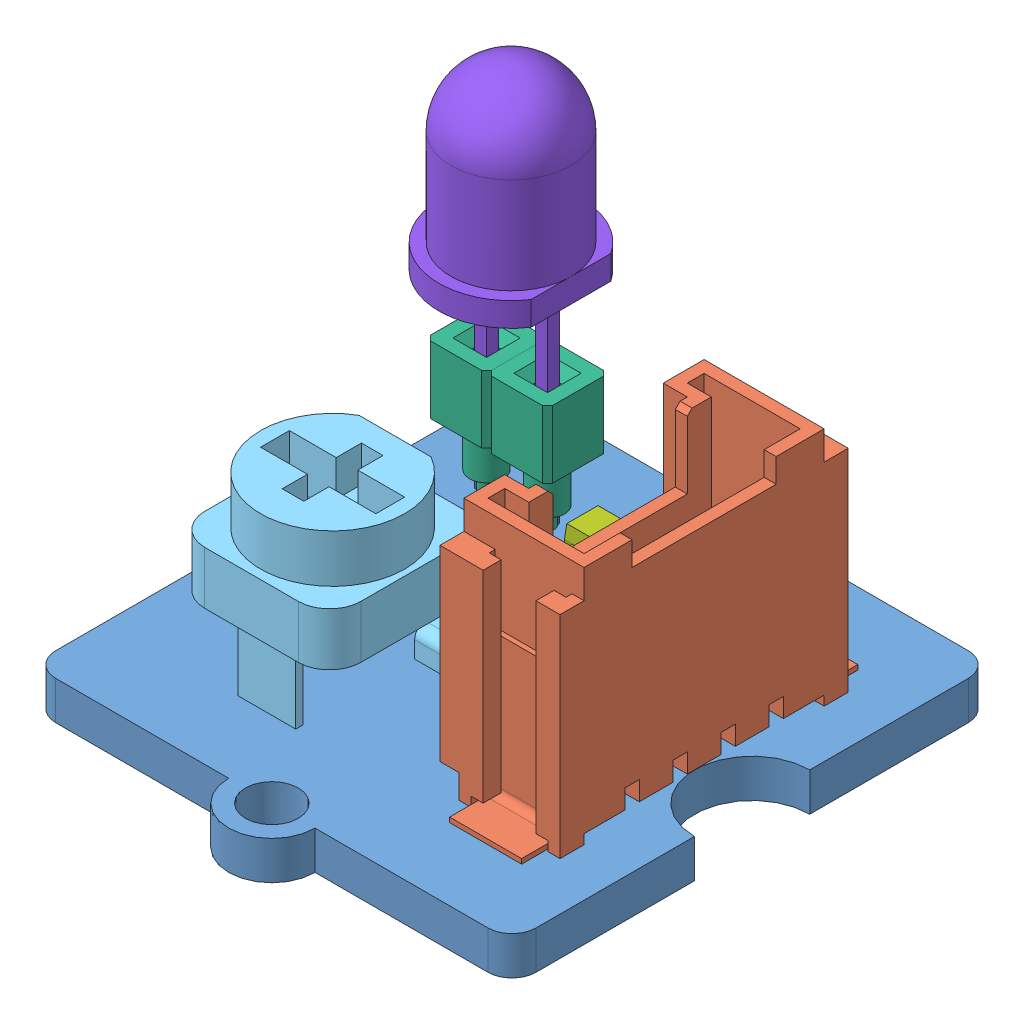
SolidWorks assembly Grove LED Rouge, configuration Défaut. Lengths in mm.
Overall size (20 19.1 23.6).
11 component instances, 8 part files, 16 mates.
Components (placement in the parent):
- PCB grove 20x20-1: PCB grove 20x20 [Défaut] at (7.4555 -4.1841 0) size (20 1.6 23.6)
- Connecteur Grove (droit CMS)-1: Connecteur Grove (droit CMS) [Défaut] at (10.4555 -2.5841 0) x (-1 0 0) z (0 1 0) size (6.5 14 10)
- 603 resistor 102-2: 603 resistor 102 [Default] at (3.6365 -2.5841 -1.49) size (2.36 0.62 1.03)
- 603 cap on pad-1: 603 cap on pad [Défaut] at (8.4655 -2.5841 -6.62) x (0 0 1) z (-1 0 0) size (2.76 0.91 1.12)
- 603 resistor 102-3: 603 resistor 102 [Default] at (6.6365 -2.5841 -1.49) size (2.36 0.62 1.03)
- 603 resistor 102-4: 603 resistor 102 [Default] at (6.6365 -2.5841 -2.99) size (2.36 0.62 1.03)
- Pot - RES_VAR1-1: Pot - RES_VAR1 [Défaut] at (4.0824 2.7159 4.0972) size (6.5 10.5 7.06)
- Contact F-1: Contact F [Défaut] at (0.621 0.0871 -5.7728) size (2.54 7.5 2.54)
- ssot3-1: ssot3 [Default] at (6.0932 -2.5841 -5.7439) size (3 1.13 3.09)
- LED 5mm Rouge-3: LED 5mm Rouge [Default] at (1.591 5.8159 -5.8228) x (1 0 0) z (0 1 0) size (5.5 6 17.5)
- Contact F-2: Contact F [Défaut] at (3.161 0.0871 -5.7728) size (2.54 7.5 2.54)
Mates (geometry in assembly coordinates):
- Distance1: distance = 2 mm aligned: plane of PCB grove 20x20-1 through (17.4555 -2.5841 0) normal (1 0 0); plane of Connecteur Grove (droit CMS)-1 through (15.4555 7.4159 6) normal (1 0 0)
- Distance2: distance = 4 mm aligned: plane of Connecteur Grove (droit CMS)-1 through (14.4555 7.4159 -6) normal (0 0 -1); plane of PCB grove 20x20-1 through (7.4555 -2.5841 -10) normal (0 0 -1)
- Coïncidente16: coincident anti-aligned: plane of PCB grove 20x20-1 through (7.4555 -2.5841 0) normal (0 1 0); plane of 603 resistor 102-2 through (3.6365 -2.5841 -1.49) normal (0 -1 0)
- Distance12: distance = 8 mm: plane of PCB grove 20x20-1 through (7.4555 -2.5841 -10) normal (0 0 -1); line of 603 resistor 102-2 through (4.8175 -2.5841 -2) axis (-1 0 0)
- Distance13: distance = 5 mm: line of 603 resistor 102-2 through (2.4555 -2.5841 -2) axis (0 0 1); plane of PCB grove 20x20-1 through (-2.5445 -2.5841 0) normal (-1 0 0)
- Coïncidente24: coincident anti-aligned: plane of PCB grove 20x20-1 through (7.4555 -2.5841 0) normal (0 1 0); plane of 603 cap on pad-1 through (8.4655 -2.5841 -6.62) normal (0 -1 0)
- Distance17: distance = 10.5 mm: line of PCB grove 20x20-1 through (-2.5445 -2.5841 9) axis (0 0 -1); line of 603 cap on pad-1 through (7.9555 -2.5841 -5.24) axis (0 0 -1)
- Distance18: distance = 2 mm: line of PCB grove 20x20-1 through (-1.5445 -2.5841 -10) axis (1 0 0); line of 603 cap on pad-1 through (7.9555 -2.5841 -8) axis (1 0 0)
- Verrouiller1: lock: unknown of PCB grove 20x20-1; unknown of ?
- Verrouiller2: lock: unknown of PCB grove 20x20-1; unknown of ?
- Verrouiller3: lock: unknown of PCB grove 20x20-1; unknown of ?
- Coïncidente30: coincident anti-aligned: plane of PCB grove 20x20-1 through (7.4555 -2.5841 0) normal (0 1 0); plane of ssot3-1 through (6.0932 -2.5841 -5.7439) normal (0 -1 0)
- Coïncidente31: coincident anti-aligned: plane of Contact F-2 through (2.861 2.8871 -6.0728) normal (0 0 1); plane of LED 5mm Rouge-3 through (1.591 5.8159 -6.0728) normal (0 0 -1)
- Coïncidente32: coincident anti-aligned: plane of Contact F-1 through (0.321 2.8871 -5.4728) normal (1 0 0); plane of LED 5mm Rouge-3 through (0.321 5.8159 -6.0728) normal (-1 0 0)
- Coïncidente33: coincident aligned: plane of PCB grove 20x20-1 through (7.4555 -4.1841 0) normal (0 -1 0); plane of LED 5mm Rouge-3 through (0.321 -4.1841 -6.0728) normal (0 -1 0)
- Coïncidente34: coincident anti-aligned: plane of PCB grove 20x20-1 through (7.4555 -2.5841 0) normal (0 1 0); plane of Connecteur Grove (droit CMS)-1 through (10.4555 -2.5841 0) normal (0 -1 0)
